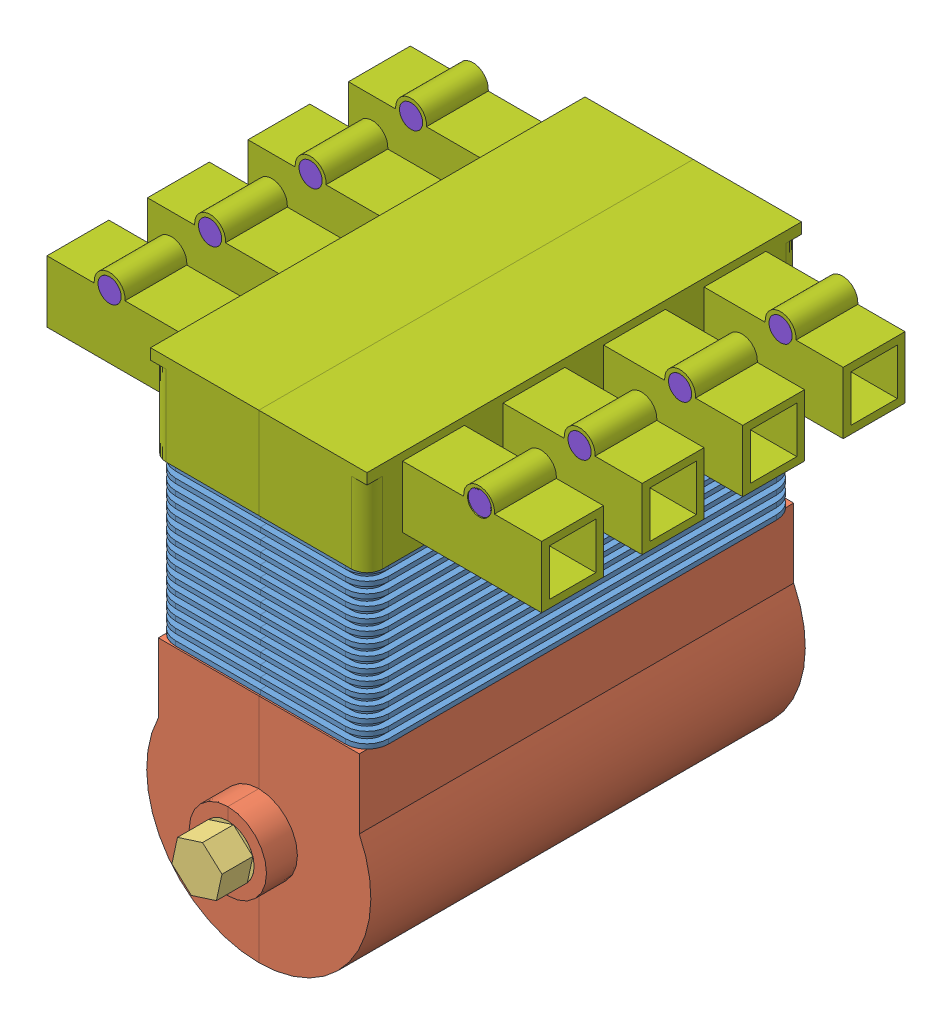
SolidWorks assembly Engine, configuration Default. Lengths in mm.
Overall size (320 315.5 361).
27 component instances, 8 part files, 54 mates.
Components (placement in the parent):
- 5. Upper block-1: 5. Upper block [Default] at (-72.5453 170.9898 493.4433) x (0 0 -1) z (1 0 0) size (279 110 69)
- 6. Lower Block-1: 6. Lower Block [Default] at (-72.5453 93.9898 498.4433) size (72.5 149.5 321)
- 4. Crankshaft-1: 4. Crankshaft [Default] at (-72.5453 93.9898 222.4433) x (0 0 -1) z (-0.672731 -0.739887 0) size (361 92 88)
- 3. Connecting Rod-1: 3. Connecting Rod [Default] at (-54.0482 77.1715 455.4433) x (0.988049 0.154143 0) z (0 0 1) size (42 160.15 20)
- 1.Piston-2: 1.Piston [Default] at (-72.5453 165.2373 455.4433) size (50 64.17 50)
- 2. Piston Pin-2: 2. Piston Pin [Default] at (-72.5453 195.7373 455.4433) x (-0.90396 0.427618 0) z (0 0 1) size (12.5 12.5 49)
- 3. Connecting Rod-2: 3. Connecting Rod [Default] at (-54.0482 77.1715 260.4433) x (-0.988049 -0.154143 0) z (0 0 -1) size (42 160.15 20)
- 1.Piston-3: 1.Piston [Default] at (-72.5453 165.2373 260.4433) x (-1 0 0) z (0 0 -1) size (50 64.17 50)
- 2. Piston Pin-3: 2. Piston Pin [Default] at (-72.5453 195.7373 260.4433) x (-0.173648 0.984808 0) z (0 0 -1) size (12.5 12.5 49)
- 1.Piston-5: 1.Piston [Default] at (-72.5453 198.8739 390.4433) size (50 64.17 50)
- 3. Connecting Rod-4: 3. Connecting Rod [Default] at (-91.0425 110.8081 390.4433) x (0.988049 -0.154143 0) z (0 0 1) size (42 160.15 20)
- 2. Piston Pin-5: 2. Piston Pin [Default] at (-72.5453 229.3739 390.4433) x (-0.90396 0.427618 0) z (0 0 1) size (12.5 12.5 49)
- 1.Piston-6: 1.Piston [Default] at (-72.5453 198.8739 325.4433) x (-1 0 0) z (0 0 -1) size (50 64.17 50)
- 2. Piston Pin-6: 2. Piston Pin [Default] at (-72.5453 229.3739 325.4433) x (0.578092 -0.815971 0) z (0 0 -1) size (12.5 12.5 49)
- 3. Connecting Rod-5: 3. Connecting Rod [Default] at (-91.0425 110.8081 325.4433) x (-0.988049 0.154143 0) z (0 0 -1) size (42 160.15 20)
- 5. Upper block-2: 5. Upper block [Default] at (-72.5453 170.9898 222.4433) x (0 0 1) z (-1 0 0) size (279 110 69)
- 6. Lower Block-2: 6. Lower Block [Default] at (-72.5453 93.9898 217.4433) x (-1 0 0) z (0 0 -1) size (72.5 149.5 321)
- 7. Air intake pipes-1: 7. Air intake pipes [Default] at (-142.5453 280.9898 357.9433) x (0 1 0) z (0 0 1) size (65 160 281)
- 8. Valve-1: 8. Valve [Default] at (-191.6311 320.9833 455.4433) x (-0.999898 0.014277 0) z (0 0 -1) size (42 43.5 40)
- 8. Valve-2: 8. Valve [Default] at (-191.5911 320.9862 390.4433) x (-0.999971 0.007629 0) z (0 0 -1) size (42 43.5 40)
- 8. Valve-3: 8. Valve [Default] at (-191.4955 320.9942 260.4433) x (-0.999965 -0.00831 0) z (0 0 -1) size (42 43.5 40)
- 8. Valve-4: 8. Valve [Default] at (-191.5911 320.9862 325.4433) x (-0.999971 0.007629 0) z (0 0 -1) size (42 43.5 40)
- 7. Air intake pipes-3: 7. Air intake pipes [Default] at (-2.5453 280.9898 357.9433) x (0 1 0) z (0 0 -1) size (65 160 281)
- 8. Valve-9: 8. Valve [Default] at (48.2364 321.7458 455.4433) x (-0.998826 -0.048441 0) z (0 0 -1) size (42 43.5 40)
- 8. Valve-10: 8. Valve [Default] at (47.7447 321.0211 260.4433) x (-0.998826 -0.048441 0) z (0 0 -1) size (42 43.5 40)
- 8. Valve-11: 8. Valve [Default] at (47.7447 321.0211 390.4433) x (-0.998826 -0.048441 0) z (0 0 -1) size (42 43.5 40)
- 8. Valve-12: 8. Valve [Default] at (47.7447 321.0211 325.4433) x (-0.998826 -0.048441 0) z (0 0 -1) size (42 43.5 40)
Mates (geometry in assembly coordinates):
- Coincident1: coincident aligned: plane of 5. Upper block-1 through (-72.5453 280.9898 493.4433) normal (1 0 0); plane of 6. Lower Block-1 through (-72.5453 118.9898 493.4433) normal (1 0 0)
- Coincident2: coincident anti-aligned: plane of 5. Upper block-1 through (-127.5453 170.9898 483.4433) normal (0 -1 0); plane of 6. Lower Block-1 through (-72.5453 170.9898 493.4433) normal (0 1 0)
- Width1: width anti-aligned: plane of 6. Lower Block-1 through (-72.5453 93.9898 498.4433) normal (0 0 1); plane of 5. Upper block-1 through (-72.5453 93.9898 217.4433) normal (0 0 -1); plane of 6. Lower Block-1 through (-72.5453 280.9898 222.4433) normal (0 0 -1); plane of 5. Upper block-1 through (-72.5453 280.9898 493.4433) normal (0 0 1)
- Concentric1: concentric anti-aligned: cylinder of 6. Lower Block-1 through (-72.5453 93.9898 493.4433) axis (0 0 1) radius 17; cylinder of 4. Crankshaft-1 through (-72.5453 93.9898 518.4433) axis (0 0 -1) radius 17
- Coincident5: coincident aligned: plane of 6. Lower Block-1 through (-72.5453 93.9898 518.4433) normal (0 0 1); plane of 4. Crankshaft-1 through (-72.5453 93.9898 518.4433) normal (0 0 1)
- Concentric4: concentric anti-aligned: cylinder of 1.Piston-2 through (-72.5453 195.7373 430.4433) axis (0 0 1) radius 6.25; cylinder of 2. Piston Pin-2 through (-72.5453 195.7373 479.9433) axis (0 0 -1) radius 6.25
- Width2: width anti-aligned: plane of 1.Piston-2 through (-72.5453 195.7373 443.4433) normal (0 0 1); plane of 1.Piston-2 through (-72.5453 195.7373 467.4433) normal (0 0 -1); plane of 2. Piston Pin-2 through (-72.5453 195.7373 430.9433) normal (0 0 -1); plane of 2. Piston Pin-2 through (-72.5453 195.7373 479.9433) normal (0 0 1)
- Concentric5: concentric aligned: cylinder of 3. Connecting Rod-1 through (-72.5453 195.7373 465.4433) axis (0 0 -1) radius 6.25; cylinder of 2. Piston Pin-2 through (-72.5453 195.7373 479.9433) axis (0 0 -1) radius 6.25
- Width3: width anti-aligned: plane of 1.Piston-2 through (-72.5453 195.7373 443.4433) normal (0 0 1); plane of 1.Piston-2 through (-72.5453 195.7373 467.4433) normal (0 0 -1); plane of 3. Connecting Rod-1 through (-54.0482 77.1715 445.4433) normal (0 0 -1); plane of 3. Connecting Rod-1 through (-54.0482 77.1715 465.4433) normal (0 0 1)
- Concentric6: concentric anti-aligned: cylinder of 4. Crankshaft-1 through (-54.0482 77.1715 455.4433) axis (0 0 1) radius 16; cylinder of 3. Connecting Rod-1 through (-54.0482 77.1715 465.4433) axis (0 0 -1) radius 16
- Concentric7: concentric anti-aligned: cylinder of 5. Upper block-1 through (-72.5453 280.9898 455.4433) axis (0 -1 0) radius 25; cylinder of 1.Piston-2 through (-72.5453 227.7373 455.4433) axis (0 1 0) radius 25
- Concentric8: concentric anti-aligned: cylinder of 1.Piston-3 through (-72.5453 195.7373 285.4433) axis (0 0 -1) radius 6.25; cylinder of 2. Piston Pin-3 through (-72.5453 195.7373 235.9433) axis (0 0 1) radius 6.25
- Width4: width anti-aligned: plane of 1.Piston-3 through (-72.5453 195.7373 272.4433) normal (0 0 -1); plane of 1.Piston-3 through (-72.5453 195.7373 248.4433) normal (0 0 1); plane of 2. Piston Pin-3 through (-72.5453 195.7373 284.9433) normal (0 0 1); plane of 2. Piston Pin-3 through (-72.5453 195.7373 235.9433) normal (0 0 -1)
- Concentric9: concentric aligned: cylinder of 3. Connecting Rod-2 through (-72.5453 195.7373 250.4433) axis (0 0 1) radius 6.25; cylinder of 2. Piston Pin-3 through (-72.5453 195.7373 235.9433) axis (0 0 1) radius 6.25
- Width5: width anti-aligned: plane of 1.Piston-3 through (-72.5453 195.7373 272.4433) normal (0 0 -1); plane of 1.Piston-3 through (-72.5453 195.7373 248.4433) normal (0 0 1); plane of 3. Connecting Rod-2 through (-54.0482 77.1715 270.4433) normal (0 0 1); plane of 3. Connecting Rod-2 through (-54.0482 77.1715 250.4433) normal (0 0 -1)
- Concentric10: concentric anti-aligned: cylinder of 4. Crankshaft-1 through (-54.0482 77.1715 260.4433) axis (0 0 -1) radius 16; cylinder of 3. Connecting Rod-2 through (-54.0482 77.1715 250.4433) axis (0 0 1) radius 16
- Concentric11: concentric anti-aligned: cylinder of 5. Upper block-1 through (-72.5453 280.9898 260.4433) axis (0 -1 0) radius 25; cylinder of 1.Piston-3 through (-72.5453 227.7373 260.4433) axis (0 1 0) radius 25
- Concentric14: concentric anti-aligned: cylinder of 1.Piston-5 through (-72.5453 229.3739 365.4433) axis (0 0 1) radius 6.25; cylinder of 2. Piston Pin-5 through (-72.5453 229.3739 414.9433) axis (0 0 -1) radius 6.25
- Width8: width anti-aligned: plane of 1.Piston-5 through (-72.5453 229.3739 378.4433) normal (0 0 1); plane of 1.Piston-5 through (-72.5453 229.3739 402.4433) normal (0 0 -1); plane of 2. Piston Pin-5 through (-72.5453 229.3739 365.9433) normal (0 0 -1); plane of 2. Piston Pin-5 through (-72.5453 229.3739 414.9433) normal (0 0 1)
- Concentric15: concentric aligned: cylinder of 3. Connecting Rod-4 through (-72.5453 229.3739 400.4433) axis (0 0 -1) radius 6.25; cylinder of 2. Piston Pin-5 through (-72.5453 229.3739 414.9433) axis (0 0 -1) radius 6.25
- Width9: width anti-aligned: plane of 1.Piston-5 through (-72.5453 229.3739 402.4433) normal (0 0 -1); plane of 1.Piston-5 through (-72.5453 229.3739 378.4433) normal (0 0 1); plane of 3. Connecting Rod-4 through (-91.0425 110.8081 400.4433) normal (0 0 1); plane of 3. Connecting Rod-4 through (-91.0425 110.8081 380.4433) normal (0 0 -1)
- Concentric16: concentric anti-aligned: cylinder of 4. Crankshaft-1 through (-91.0425 110.8081 375.4433) axis (0 0 1) radius 16; cylinder of 3. Connecting Rod-4 through (-91.0425 110.8081 400.4433) axis (0 0 -1) radius 16
- Concentric17: concentric anti-aligned: cylinder of 5. Upper block-1 through (-72.5453 280.9898 390.4433) axis (0 -1 0) radius 25; cylinder of 1.Piston-5 through (-72.5453 261.3739 390.4433) axis (0 1 0) radius 25
- Concentric18: concentric anti-aligned: cylinder of 1.Piston-6 through (-72.5453 229.3739 350.4433) axis (0 0 -1) radius 6.25; cylinder of 2. Piston Pin-6 through (-72.5453 229.3739 300.9433) axis (0 0 1) radius 6.25
- Width10: width anti-aligned: plane of 1.Piston-6 through (-72.5453 229.3739 337.4433) normal (0 0 -1); plane of 1.Piston-6 through (-72.5453 229.3739 313.4433) normal (0 0 1); plane of 2. Piston Pin-6 through (-72.5453 229.3739 349.9433) normal (0 0 1); plane of 2. Piston Pin-6 through (-72.5453 229.3739 300.9433) normal (0 0 -1)
- Concentric19: concentric aligned: cylinder of 2. Piston Pin-6 through (-72.5453 229.3739 300.9433) axis (0 0 1) radius 6.25; cylinder of 3. Connecting Rod-5 through (-72.5453 229.3739 315.4433) axis (0 0 1) radius 6.25
- Width11: width anti-aligned: plane of 1.Piston-6 through (-72.5453 229.3739 313.4433) normal (0 0 1); plane of 1.Piston-6 through (-72.5453 229.3739 337.4433) normal (0 0 -1); plane of 3. Connecting Rod-5 through (-91.0425 110.8081 315.4433) normal (0 0 -1); plane of 3. Connecting Rod-5 through (-91.0425 110.8081 335.4433) normal (0 0 1)
- Concentric20: concentric anti-aligned: cylinder of 4. Crankshaft-1 through (-91.0425 110.8081 340.4433) axis (0 0 -1) radius 16; cylinder of 3. Connecting Rod-5 through (-91.0425 110.8081 315.4433) axis (0 0 1) radius 16
- Concentric21: concentric anti-aligned: cylinder of 5. Upper block-1 through (-72.5453 280.9898 325.4433) axis (0 -1 0) radius 25; cylinder of 1.Piston-6 through (-72.5453 261.3739 325.4433) axis (0 1 0) radius 25
- Coincident6: coincident anti-aligned: plane of 5. Upper block-1 through (-72.5453 280.9898 235.4433) normal (1 0 0); plane of 5. Upper block-2 through (-72.5453 280.9898 222.4433) normal (-1 0 0)
- Coincident7: coincident aligned: plane of 5. Upper block-1 through (-127.5453 280.9898 483.4433) normal (0 1 0); plane of 5. Upper block-2 through (-17.5453 280.9898 232.4433) normal (0 1 0)
- Coincident8: coincident aligned: plane of 5. Upper block-1 through (-72.5453 280.9898 493.4433) normal (0 0 1); plane of 5. Upper block-2 through (-72.5453 280.9898 493.4433) normal (0 0 1)
- Coincident9: coincident anti-aligned: plane of 6. Lower Block-1 through (-72.5453 76.9898 493.4433) normal (1 0 0); plane of 6. Lower Block-2 through (-72.5453 76.9898 222.4433) normal (-1 0 0)
- Coincident10: coincident aligned: plane of 6. Lower Block-1 through (-72.5453 93.9898 498.4433) normal (0 0 1); plane of 6. Lower Block-2 through (-72.5453 93.9898 498.4433) normal (0 0 1)
- Coincident11: coincident aligned: plane of 6. Lower Block-1 through (-72.5453 170.9898 493.4433) normal (0 1 0); plane of 6. Lower Block-2 through (-72.5453 170.9898 222.4433) normal (0 1 0)
- Coincident12: coincident anti-aligned: plane of 5. Upper block-1 through (-127.5453 280.9898 483.4433) normal (0 1 0); plane of Air intake pipes-1 through (-142.5453 280.9898 357.9433) normal (0 -1 0)
- Coincident13: coincident anti-aligned: plane of 5. Upper block-1 through (-72.5453 280.9898 222.4433) normal (0 0 -1); plane of Air intake pipes-1 through (-127.5453 271.9898 222.4433) normal (0 0 1)
- Coincident14: coincident anti-aligned: plane of 5. Upper block-1 through (-137.5453 280.9898 483.4433) normal (-1 0 0); plane of Air intake pipes-1 through (-137.5453 271.9898 483.4433) normal (1 0 0)
- Concentric23: concentric aligned: cylinder of Air intake pipes-1 through (-192.0453 326.9898 240.4433) axis (0 0 1) radius 7.5; cylinder of 8. Valve-1 through (-192.0453 326.9898 435.4433) axis (0 0 1) radius 7.5
- Width12: width anti-aligned: plane of 8. Valve-1 through (-192.0453 326.9898 435.4433) normal (0 0 -1); plane of 7. Air intake pipes-1 through (-192.0453 326.9898 475.4433) normal (0 0 1); plane of 8. Valve-1 through (-232.5453 285.9898 475.4433) normal (0 0 1); plane of 7. Air intake pipes-1 through (-232.5453 285.9898 435.4433) normal (0 0 -1)
- Concentric24: concentric aligned: cylinder of Air intake pipes-1 through (-192.0453 326.9898 240.4433) axis (0 0 1) radius 7.5; cylinder of 8. Valve-2 through (-192.0453 326.9898 370.4433) axis (0 0 1) radius 7.5
- Width13: width aligned: plane of 8. Valve-2 through (-192.0453 326.9898 410.4433) normal (0 0 1); plane of 7. Air intake pipes-1 through (-192.0453 326.9898 370.4433) normal (0 0 -1); plane of 8. Valve-2 through (-232.5453 285.9898 410.4433) normal (0 0 1); plane of 7. Air intake pipes-1 through (-232.5453 285.9898 370.4433) normal (0 0 -1)
- Concentric25: concentric aligned: cylinder of Air intake pipes-1 through (-192.0453 326.9898 240.4433) axis (0 0 1) radius 7.5; cylinder of 8. Valve-3 through (-192.0453 326.9898 240.4433) axis (0 0 1) radius 7.5
- Concentric26: concentric aligned: cylinder of Air intake pipes-1 through (-192.0453 326.9898 240.4433) axis (0 0 1) radius 7.5; cylinder of 8. Valve-4 through (-192.0453 326.9898 305.4433) axis (0 0 1) radius 7.5
- Width14: width aligned: plane of 8. Valve-4 through (-192.0453 326.9898 345.4433) normal (0 0 1); plane of 7. Air intake pipes-1 through (-192.0453 326.9898 305.4433) normal (0 0 -1); plane of 8. Valve-4 through (-232.5453 285.9898 345.4433) normal (0 0 1); plane of 7. Air intake pipes-1 through (-232.5453 285.9898 305.4433) normal (0 0 -1)
- Width15: width aligned: plane of 7. Air intake pipes-1 through (-232.5453 285.9898 280.4433) normal (0 0 1); plane of 8. Valve-3 through (-232.5453 285.9898 240.4433) normal (0 0 -1); plane of 7. Air intake pipes-1 through (-192.0453 326.9898 280.4433) normal (0 0 1); plane of 8. Valve-3 through (-192.0453 326.9898 240.4433) normal (0 0 -1)
- Coincident17: coincident anti-aligned: plane of 5. Upper block-2 through (-17.5453 280.9898 232.4433) normal (0 1 0); plane of Air intake pipes-3 through (-2.5453 280.9898 357.9433) normal (0 -1 0)
- Coincident18: coincident anti-aligned: plane of 5. Upper block-2 through (-72.5453 280.9898 222.4433) normal (0 0 -1); plane of Air intake pipes-3 through (-72.5453 271.9898 222.4433) normal (0 0 1)
- Coincident19: coincident anti-aligned: plane of 5. Upper block-2 through (-7.5453 280.9898 232.4433) normal (1 0 0); plane of Air intake pipes-3 through (-7.5453 271.9898 232.4433) normal (-1 0 0)
- Coincident26: coincident anti-aligned: circle of 7. Air intake pipes-3; plane of 8. Valve-9 through (47.4463 327.7145 475.4433) normal (0 0 1)
- Concentric33: concentric anti-aligned: cylinder of 7. Air intake pipes-3 through (46.9547 326.9898 475.4433) axis (0 0 -1) radius 7.5; cylinder of 8. Valve-11 through (46.9547 326.9898 370.4433) axis (0 0 1) radius 7.5
- Coincident30: coincident aligned: circle of 7. Air intake pipes-3; circle of 8. Valve-11
- Coincident31: coincident aligned: circle of 7. Air intake pipes-3; circle of 8. Valve-12
- Coincident32: coincident aligned: circle of 7. Air intake pipes-3; circle of 8. Valve-10
